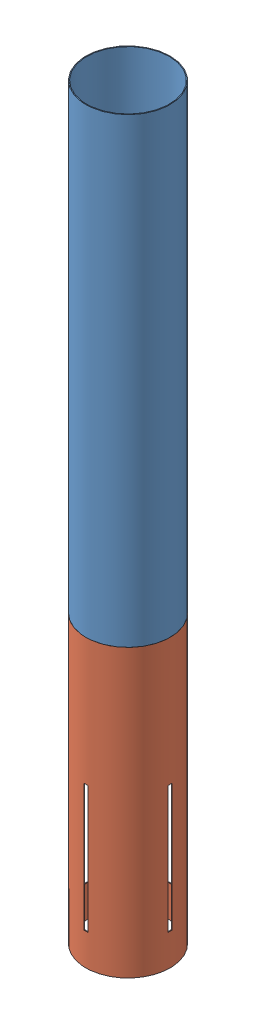
SolidWorks assembly Assem4, configuration Default. Lengths in mm.
Overall size (134.62 1193.8 134.62).
2 component instances, 2 part files, 2 mates.
Components (placement in the parent):
- BodyTubeLowerFiber-1: BodyTubeLowerFiber [Default] at (26.8553 159.5578 598.857) size (134.62 736.6 134.62)
- BodyTubeLowerCarbon-1: BodyTubeLowerCarbon [Default] at (26.8553 -297.6422 598.857) size (134.62 457.2 134.62)
Mates (geometry in assembly coordinates):
- Coincident1: coincident: plane of BodyTubeLowerFiber-1 through (26.8553 159.5578 598.857) normal (0 -1 0); plane of BodyTubeLowerCarbon-1 through (26.8553 159.5578 598.857) normal (0 1 0)
- Coincident2: coincident aligned: circle of BodyTubeLowerFiber-1; circle of BodyTubeLowerCarbon-1
